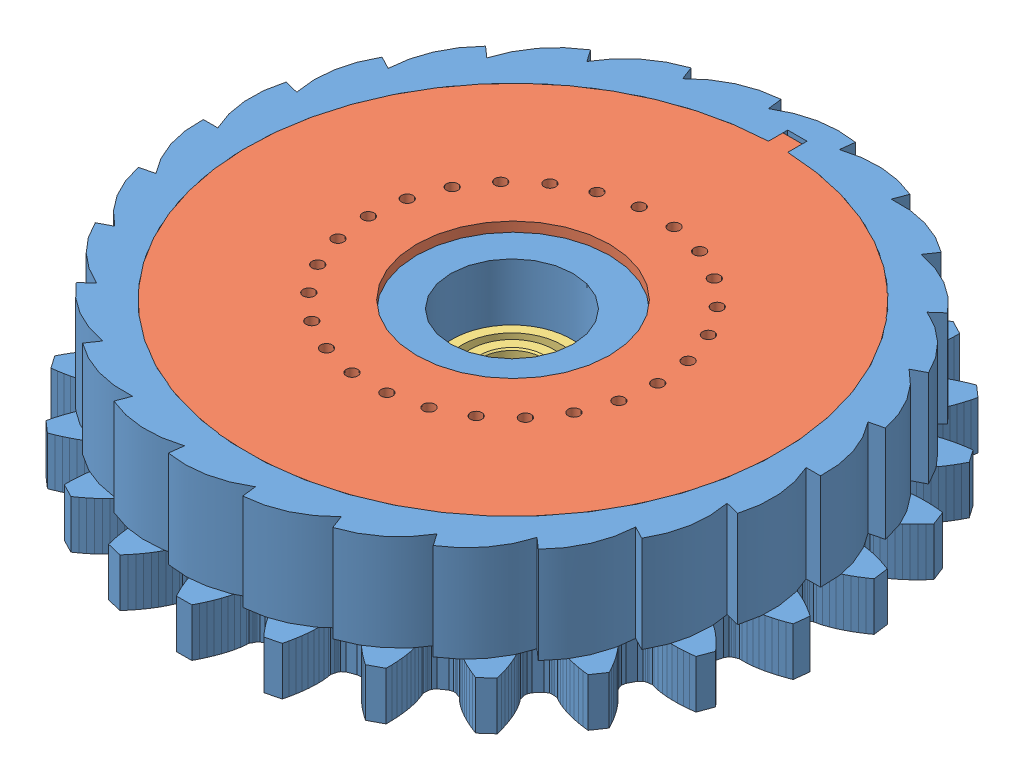
SolidWorks assembly End cap wheel assembly, configuration Default. Lengths in mm.
Overall size (80.8 15 76.92).
4 component instances, 3 part files, 6 mates.
Components (placement in the parent):
- endcap wheel-1: endcap wheel [Default] at (26.6122 32.7605 52.2161) size (68.11 15 68.39)
- selector wheel PCB-1: selector wheel PCB [Default] at (26.8584 41.7605 52.3462) x (1 0 0) z (0 1 0) size (67.78 70.24 1)
- selector wheel PCB-2: selector wheel PCB [Default] at (26.6122 28.7605 52.2161) x (-1 0 0) z (0 -1 0) size (67.78 70.24 1)
- 57155K356 ball bearing-1: 57155K356 ball bearing [57155K356] at (26.6122 34.348 52.2161) x (-0.69888 0 -0.715239) z (0 -1 0) size (12.7 12.7 3.17)
Mates (geometry in assembly coordinates):
- Coincident1: coincident aligned: circle of endcap wheel-1; circle of selector wheel PCB-1
- Coincident2: coincident anti-aligned: plane of endcap wheel-1 through (25.8584 41.7605 22.8644) normal (1 0 0); plane of selector wheel PCB-1 through (25.8584 42.7605 24.8644) normal (-1 0 0)
- Coincident3: coincident aligned: circle of endcap wheel-1; circle of selector wheel PCB-2
- Coincident4: coincident anti-aligned: plane of endcap wheel-1 through (27.6122 28.7605 22.7343) normal (-1 0 0); plane of selector wheel PCB-2 through (27.6122 27.7605 24.7343) normal (1 0 0)
- Concentric1: concentric anti-aligned: cylinder of endcap wheel-1 through (26.6122 14.8 52.2161) axis (0 1 0) radius 6.35; cylinder of 57155K356 ball bearing-1 through (26.6122 32.7605 52.2161) axis (0 -1 0) radius 6.35
- Coincident6: coincident anti-aligned: plane of endcap wheel-1 through (47.9635 32.7605 51.6578) normal (0 1 0); plane of 57155K356 ball bearing-1 through (31.0404 32.7605 47.8892) normal (0 -1 0)
